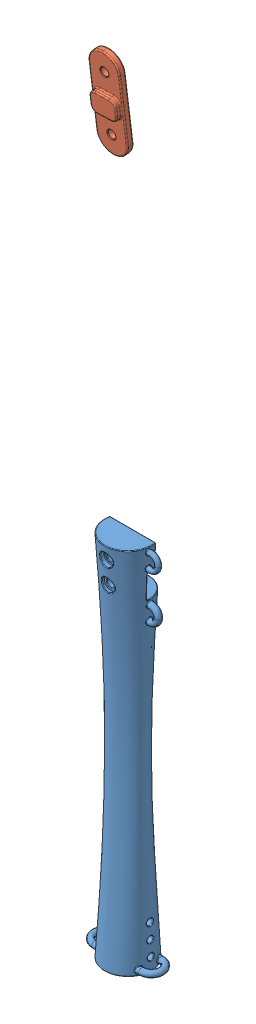
SolidWorks assembly 09_BA_001, configuration Default. Lengths in mm.
Overall size (75.2 116.94 0).
15 component instances, 10 part files, 48 mates.
Components (placement in the parent):
- 03_01_FB_R_004-1: 03_01_FB_R_004 [Default] at (-44.1835 -422.7421 30.4544) x (1 0 0) z (0 -0.087156 0.996195) size (87.64 320.86 63.22) (hidden)
- 04_01_KT_R_002-1: 04_01_KT_R_002 [Default] at (-35.7099 -501.4017 28.2279) size (76.83 156.89 75.86) (hidden)
- 04_05_BL_001-1: 04_05_BL_001 [Default] at (-43.0902 -517.9682 28.3279) x (0.731564 0.681773 0) z (0 0 1) size (62.75 16 5.9) (hidden)
- 04_06_FL_001-1: 04_06_FL_001 [Default] at (-32.1081 -509.7132 22.2279) x (0.453457 -0.891278 0) z (0 0 1) size (67.43 16 5.9) (hidden)
- 04_02_KB_R_002-1: 04_02_KB_R_002 [Default] at (-44.3343 -542.7719 28.2279) size (78.46 85.69 76.61) (hidden)
- 05_01_TI_R_002-1: 05_01_TI_R_002 [Default] at (-44.7333 -552.7719 28.2531) size (59.1 200.55 39.98) (hidden)
- MuscleOrigins_003-1: MuscleOrigins_003 [Default] at (-53.8778 -91.0932 28.1049) size (120.4 110.52 92.58) (hidden)
- 05_01_TI_R_003-1: 05_01_TI_R_003 [Default] at (-44.7333 -552.7719 29.2538) size (59.1 300.58 40.08) (hidden)
- 03_01_FB_R_004_ribLink-1: 03_01_FB_R_004_ribLink [Default] at (-54.1468 -275.405 33.3065) x (-0.999255 -0.038445 -0.003363) z (0 0.087156 -0.996195) size (25.4 75.4 9) (hidden)
- 04_03_KT_L_001-1: 04_03_KT_L_001 [Default] at (-58.1209 -495.9413 22.1279) x (-0.5 0.866025 0) z (0 0 1) size (77.01 157.24 74.14) (hidden)
- 04_05_BL_001-2: 04_05_BL_001 [Default] at (-61.3129 -510.5566 16.1279) x (-0.048018 0.998846 0) z (0 0 1) size (62.75 16 5.9) (hidden)
- 04_05_BL_001-3: 04_05_BL_001 [Default] at (-49.2868 -513.2286 16.1279) x (0.466469 0.884538 0) z (0 0 1) size (62.75 16 5.9) (hidden)
- 04_06_FL_001-2: 04_06_FL_001 [Default] at (-40.4588 -516.4825 22.2279) x (-0.778166 0.628059 0) z (0 0 1) size (67.43 16 5.9) (hidden)
- 04_03_KT_L_001-2: 04_03_KT_L_001 [Default] at (-43.7887 -500.6553 22.1279) x (0.5 0.866025 0) z (0 0 1) size (77.01 157.24 74.14) (hidden)
- 04_06_FL_001-3: 04_06_FL_001 [Default] at (-43.5949 -521.4306 22.2279) x (-0.900112 0.435659 0) z (0 0 1) size (67.43 16 5.9) (hidden)
Mates (geometry in assembly coordinates):
- Concentric2: concentric aligned: cylinder of 6630T310_METRIC BLACK POLYPROPYLENE BALL KNOB-1; cylinder of 92997A108_CORROSION-RESISTANT SETUP STUD-1 through (-50.1927 -92.0259 99.2679) axis (0.194905 -0.763657 0.6155) radius 3.02
- Coincident1: coincident anti-aligned: plane of 6630T310_METRIC BLACK POLYPROPYLENE BALL KNOB-1 through (-59.9379 -53.8431 68.4929) normal (0.194905 -0.763657 0.6155); plane of 92997A108_CORROSION-RESISTANT SETUP STUD-1 through (-59.9379 -53.8431 68.4929) normal (-0.194905 0.763657 -0.6155)
- Concentric3: concentric anti-aligned: cylinder of 92997A108_CORROSION-RESISTANT SETUP STUD-1 through (-50.1927 -92.0259 99.2679) axis (0.194905 -0.763657 0.6155) radius 3.02; cylinder of 03_02_FemurHead_Right-1 through (-50.1927 -92.0259 99.2679) axis (-0.194905 0.763657 -0.6155) radius 3.125
- Coincident2: coincident anti-aligned: plane of 92997A108_CORROSION-RESISTANT SETUP STUD-1 through (-50.1927 -92.0259 99.2679) normal (0.194905 -0.763657 0.6155); plane of 03_02_FemurHead_Right-1 through (-50.1927 -92.0259 99.2679) normal (-0.194905 0.763657 -0.6155)
- Coincident5: coincident anti-aligned: plane of 03_01_FB_R_004-1 through (-6.5372 -422.5618 28.3929) normal (0 -0.087156 0.996195); plane of 04_01_KT_R_002-1 through (-0.3526 -500.8172 21.5464) normal (0 0.087156 -0.996195)
- Coincident6: coincident anti-aligned: plane of 03_01_FB_R_004-1 through (-23.7099 -422.7459 30.4972) normal (0 -0.996195 -0.087156); plane of 04_01_KT_R_002-1 through (-0.3526 -423.1463 35.0744) normal (0 0.996195 0.087156)
- Concentric5: concentric anti-aligned: cylinder of 03_01_FB_R_004-1 through (-23.7099 -414.5019 56.7427) axis (0 0.087156 -0.996195) radius 3.2; cylinder of 04_01_KT_R_002-1 through (-23.7099 -408.5695 -11.0655) axis (0 -0.087156 0.996195) radius 3.25
- Concentric6: concentric aligned: cylinder of 04_01_KT_R_002-1 through (-25.9899 -502.0317 65.2279) axis (0 0 -1) radius 3; cylinder of 04_05_BL_001-1 through (-25.9899 -502.0317 34.2279) axis (0 0 -1) radius 3.15
- Coincident7: coincident anti-aligned: plane of 04_01_KT_R_002-1 through (-67.9127 -529.7716 34.2279) normal (0 0 -1); plane of 04_05_BL_001-1 through (-25.9899 -502.0317 34.2279) normal (0 0 1)
- Concentric7: concentric anti-aligned: cylinder of 04_01_KT_R_002-1 through (-43.7699 -486.7917 -8.7721) axis (0 0 1) radius 3; cylinder of 04_06_FL_001-1 through (-43.7699 -486.7917 28.1279) axis (0 0 -1) radius 3.15
- Coincident8: coincident anti-aligned: plane of 04_01_KT_R_002-1 through (-67.9127 -529.7716 22.2279) normal (0 0 1); plane of 04_06_FL_001-1 through (-20.4463 -532.6346 22.2279) normal (0 0 -1)
- Concentric8: concentric anti-aligned: cylinder of 04_05_BL_001-1 through (-60.1905 -533.9046 34.2279) axis (0 0 -1) radius 3.15; cylinder of 04_02_KB_R_002-1 through (-60.1905 -533.9046 13.2279) axis (0 0 1) radius 3.1
- Coincident9: coincident anti-aligned: plane of 04_05_BL_001-1 through (-25.9899 -502.0317 34.2279) normal (0 0 1); plane of 04_02_KB_R_002-1 through (-34.6475 -500.9122 34.2279) normal (0 0 -1)
- Concentric9: concentric anti-aligned: cylinder of 04_06_FL_001-1 through (-20.4463 -532.6346 28.1279) axis (0 0 -1) radius 3.15; cylinder of 04_02_KB_R_002-1 through (-20.4463 -532.6346 13.2279) axis (0 0 1) radius 3.1
- LimitAngle1: limit planar angle = 0 rad aligned: plane of 04_02_KB_R_002-1 through (-7.8343 -502.7719 65.7279) normal (1 0 0); plane of 04_01_KT_R_002-1 through (-5.7099 -452.6619 65.2279) normal (1 0 0)
- Coincident11: coincident anti-aligned: plane of 04_02_KB_R_002-1 through (-84.2579 -542.7719 25.3636) normal (0 0 1); plane of 05_01_TI_R_002-1 through (-63.8297 -552.7719 25.3636) normal (0 0 -1)
- Parallel11: parallel anti-aligned: plane of 04_02_KB_R_002-1 through (-84.2579 -552.7719 28.2279) normal (0 -1 0); plane of 05_01_TI_R_002-1 through (-44.7333 -552.7719 28.2531) normal (0 1 0)
- Parallel8: parallel aligned: 
- Parallel9: parallel: plane of assembly through (0 0 0) normal (0 0 1); plane of assembly; plane of 04_01_KT_R_002-1 through (-35.7099 -501.4017 -8.7721) normal (0 0 -1)
- Concentric10: concentric aligned: cylinder of 04_02_KB_R_002-1 through (-44.7333 -581.6719 -9.6456) axis (0 0 1) radius 3.25; cylinder of 05_01_TI_R_002-1 through (-44.7333 -581.6719 9.1567) axis (0 0 1) radius 3.25
- Coincident13: coincident: point of 03_01_FB_R_004-1; point of MuscleOrigins_003-1
- Coincident14: coincident anti-aligned: plane of 04_01_KT_R_002-1 through (-5.7099 -452.6619 65.2279) normal (1 0 0); plane of Patella_v2-1 through (-20.8551 -480.4862 37.238) normal (-1 0 0)
- Parallel10: parallel anti-aligned: plane of 04_01_KT_R_002-1 through (-48.7099 -452.6619 11.2279) normal (0 0 1); plane of Patella_v2-1 through (-28.4751 -483.0262 27.078) normal (0 0 -1)
- KneeAngle: planar angle = 0 rad aligned: plane of 04_02_KB_R_002-1 through (-7.8343 -502.7719 65.7279) normal (1 0 0); plane of 04_01_KT_R_002-1 through (-5.7099 -452.6619 65.2279) normal (1 0 0)
- Coincident15: coincident anti-aligned: plane of 04_02_KB_R_002-1 through (-84.2579 -542.7719 25.3636) normal (0 0 1); plane of 05_01_TI_R_003-1 through (-63.8297 -552.7719 25.3636) normal (0 0 -1)
- Concentric11: concentric aligned: cylinder of 04_02_KB_R_002-1 through (-44.7333 -563.2719 -9.6456) axis (0 0 1) radius 3.25; cylinder of 05_01_TI_R_003-1 through (-44.7333 -563.2719 10.1574) axis (0 0 1) radius 3.25
- Concentric12: concentric aligned: cylinder of 04_02_KB_R_002-1 through (-44.7333 -581.6719 -9.6456) axis (0 0 1) radius 3.25; cylinder of 05_01_TI_R_003-1 through (-44.7333 -581.6719 10.1574) axis (0 0 1) radius 3.25
- Concentric13: concentric aligned: cylinder of 03_01_FB_R_004-1 through (-54.1468 -273.6018 12.6964) axis (0 -0.087156 0.996195) radius 3.2; cylinder of Part2^09_BA_001-1 through (-54.1468 -274.9692 28.3255) axis (0 -0.087156 0.996195) radius 3.2
- Coincident17: coincident anti-aligned: plane of 03_01_FB_R_004-1 through (-29.1237 -262.0649 34.4736) normal (0 0.087156 -0.996195); plane of Part2^09_BA_001-1 through (-54.1468 -275.405 33.3065) normal (0 -0.087156 0.996195)
- Parallel12: parallel aligned: plane of 03_01_FB_R_004-1 through (-71.7137 -150.1086 44.2685) normal (-0.999255 -0.038445 -0.003363); plane of Part2^09_BA_001-1 through (-69.1682 -215.3321 33.5431) normal (-0.999255 -0.038445 -0.003363)
- Coincident18: coincident anti-aligned: plane of 04_06_FL_001-2 through (-166.3459 -573.8058 58.5692) normal (0 0 1); plane of 04_03_KT_L_001-2 through (-190.4887 -616.7856 58.5692) normal (0 0 -1)
- Concentric14: concentric aligned: cylinder of 04_06_FL_001-2 through (-166.3459 -573.8058 58.5692) axis (0 0 -1) radius 3.15; cylinder of 04_03_KT_L_001-2 through (-166.3459 -573.8058 89.5692) axis (0 0 -1) radius 3
- Coincident19: coincident anti-aligned: plane of 04_05_BL_001-3 through (-38.3831 -492.5525 16.1279) normal (0 0 -1); plane of 04_03_KT_L_001-2 through (-35.3211 -542.7287 16.1279) normal (0 0 1)
- Concentric15: concentric anti-aligned: cylinder of 04_05_BL_001-3 through (-38.3831 -492.5525 22.0279) axis (0 0 -1) radius 3.15; cylinder of 04_03_KT_L_001-2 through (-38.3831 -492.5525 -14.8721) axis (0 0 1) radius 3
- Coincident20: coincident anti-aligned: plane of 04_03_KT_L_001-1 through (-17.4505 -509.6449 16.1279) normal (0 0 1); plane of 04_05_BL_001-2 through (-62.4353 -487.2086 16.1279) normal (0 0 -1)
- Concentric16: concentric anti-aligned: cylinder of 04_03_KT_L_001-1 through (-62.4353 -487.2086 -14.8721) axis (0 0 1) radius 3; cylinder of 04_05_BL_001-2 through (-62.4353 -487.2086 22.0279) axis (0 0 -1) radius 3.15
- Coincident21: coincident anti-aligned: plane of 04_06_FL_001-2 through (-60.4713 -500.3304 28.1279) normal (0 0 1); plane of 04_03_KT_L_001-2 through (-35.3211 -542.7287 28.1279) normal (0 0 -1)
- Concentric17: concentric aligned: cylinder of 04_06_FL_001-2 through (-60.4713 -500.3304 28.1279) axis (0 0 -1) radius 3.15; cylinder of 04_03_KT_L_001-2 through (-60.4713 -500.3304 59.1279) axis (0 0 -1) radius 3
- Coincident22: coincident anti-aligned: plane of 04_03_KT_L_001-1 through (-17.4505 -509.6449 28.1279) normal (0 0 -1); plane of 04_06_FL_001-3 through (-66.7436 -510.2265 28.1279) normal (0 0 1)
- Concentric18: concentric aligned: cylinder of 04_03_KT_L_001-1 through (-66.7436 -510.2265 59.1279) axis (0 0 -1) radius 3; cylinder of 04_06_FL_001-3 through (-66.7436 -510.2265 28.1279) axis (0 0 -1) radius 3.15
- Concentric19: concentric aligned: cylinder of 04_02_KB_R_002-1 through (-20.4463 -532.6346 66.1013) axis (0 0 -1) radius 1.5; cylinder of 04_06_FL_001-2 through (-20.4463 -532.6346 28.1279) axis (0 0 -1) radius 3.15
- Concentric20: concentric aligned: circle of 04_02_KB_R_002-1; cylinder of 04_05_BL_001-3 through (-60.1905 -533.9046 22.0279) axis (0 0 -1) radius 3.15
- Concentric21: concentric aligned: circle of 04_02_KB_R_002-1; cylinder of 04_05_BL_001-2 through (-60.1905 -533.9046 22.0279) axis (0 0 -1) radius 3.15
- Concentric22: concentric anti-aligned: circle of 04_02_KB_R_002-1; cylinder of 04_06_FL_001-3 through (-20.4463 -532.6346 28.1279) axis (0 0 -1) radius 3.15
- Coincident25: coincident aligned: plane of 04_06_FL_001-1 through (-20.4463 -532.6346 22.2279) normal (0 0 -1); plane of 04_06_FL_001-2 through (-60.4713 -500.3304 22.2279) normal (0 0 -1)
- Coincident26: coincident aligned: plane of 04_06_FL_001-2 through (-60.4713 -500.3304 22.2279) normal (0 0 -1); plane of 04_06_FL_001-3 through (-66.7436 -510.2265 22.2279) normal (0 0 -1)
- Angle1: planar angle = 1.047198 rad aligned: plane of 04_03_KT_L_001-2 through (-70.9986 -450.3046 -14.8721) normal (0.5 0.866025 0); plane of 04_02_KB_R_002-1 through (-7.8343 -502.7719 65.7279) normal (1 0 0)
- Angle2: planar angle = 2.094395 rad aligned: plane of 04_03_KT_L_001-1 through (-115.3309 -494.3305 -14.8721) normal (-0.5 0.866025 0); plane of 04_02_KB_R_002-1 through (-7.8343 -502.7719 65.7279) normal (1 0 0)
